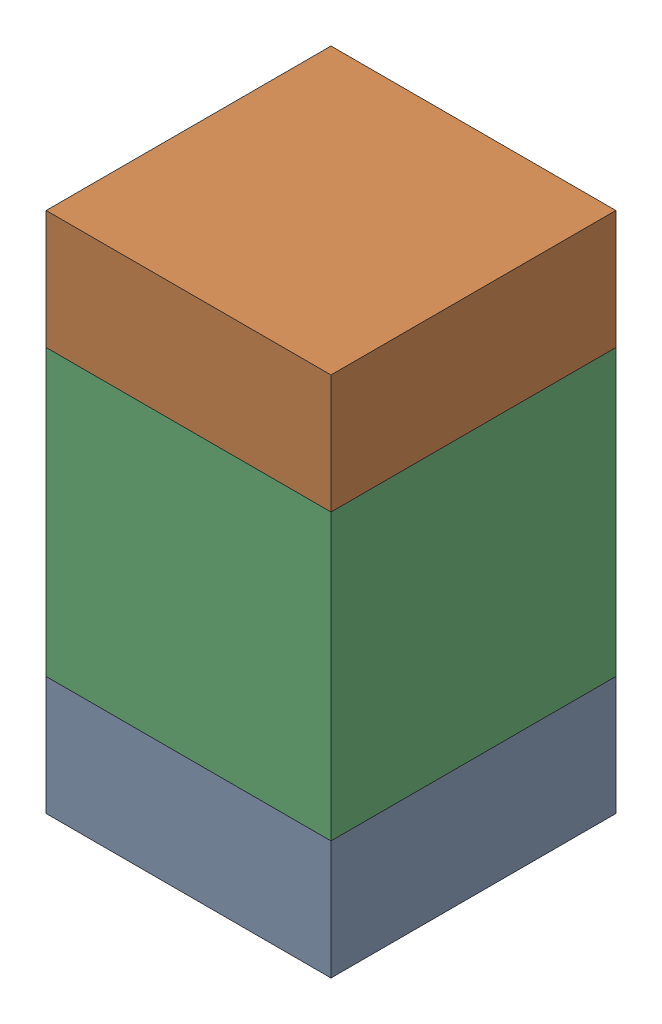
SolidWorks assembly C102_2PCB, configuration Default. Lengths in mm.
Overall size (0.6 1.1 0.6).
6 component instances, 2 part files, 0 mates.
Components (placement in the parent):
- 854785296-1: 854785296 [Default] at (110.1 99.275 0) size (0.6 0.25 0.6)
  - Extruded_10-1: Extruded_10 [Default] at origin size (0.6 0.25 0.6)
- 854785296-2: 854785296 [Default] at (110.1 100.125 0) size (0.6 0.25 0.6)
  - Extruded_10-1: Extruded_10 [Default] at origin size (0.6 0.25 0.6)
- 761606048-1: 761606048 [Default] at (110.1 99.7 0) size (0.6 0.6 0.6)
  - Extruded_9-1: Extruded_9 [Default] at origin size (0.6 0.6 0.6)
